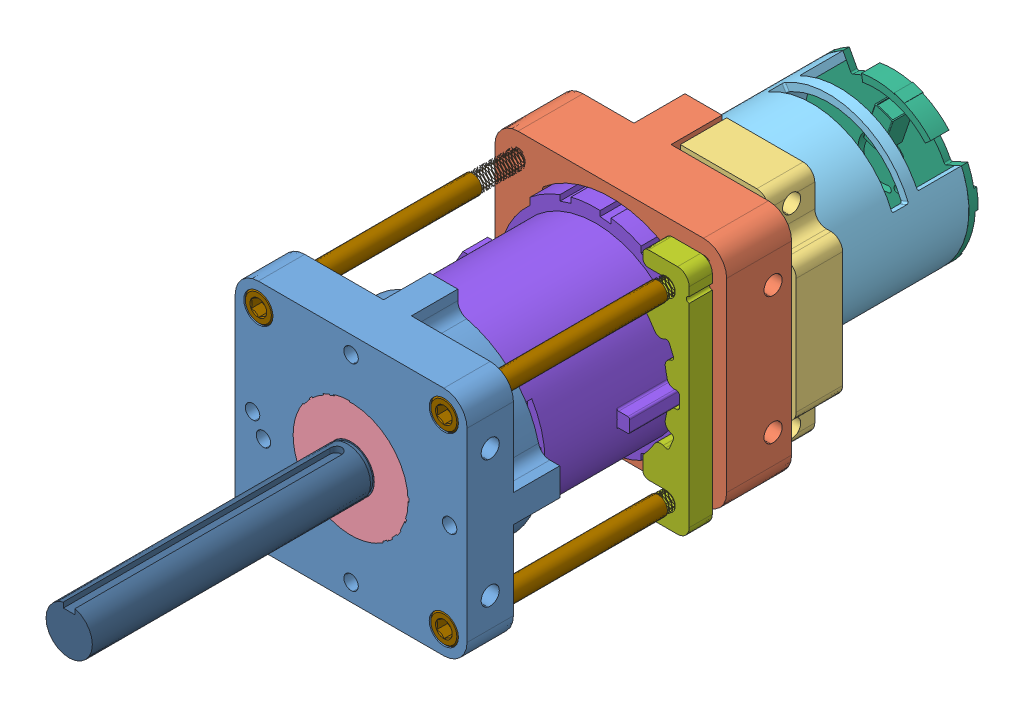
SolidWorks assembly dewut_assy, configuration Default. Lengths in mm.
Overall size (63.91 63.5 231.44).
15 component instances, 10 part files, 0 mates.
Components (placement in the parent):
- drillgb_billet_front-1: drillgb_billet_front [Default] at origin size (63.5 63.5 25.4)
- drillgb_billet_mid-1: drillgb_billet_mid [Default] at (0 0 -77.47) size (63.5 63.5 31.75)
- drillgb_billet_motor_clamp-1: drillgb_billet_motor_clamp [Default] at (0 31.75 -77.47) x (0 -1 0) z (0 0 1) size (63.5 31.75 12.7)
- fake_FR8ZZ-1: fake_FR8ZZ [Default] at (0 0 17.4625) size (31.75 31.75 7.94)
- fake_FR8ZZ-2: fake_FR8ZZ [Default] at (0 0 17.4625) x (1 0 0) z (0 0 -1) size (31.75 31.75 7.94)
- dewalt_motor-1: dewalt_motor [Default] at (0 0 -120.32) x (0.998041 0.062557 0) z (0 0 1) size (59.19 56.05 89.26)
  - dewalt_motor_shell-1: dewalt_motor_shell [Default] at origin size (47 47 80.75)
  - dewalt_motor_endcap-1: dewalt_motor_endcap [Default] x (0.92388 -0.382683 0) z (0 0 -1) size (47 41.2 14.33)
- drillgb_gear_selector_lock_layer_6_v2-1: drillgb_gear_selector_lock_layer_6_v2 [Default] at (-31.75 -31.75 -41.7842) size (12.7 63.5 6.35)
- dewalt_397892_geometry_model-1: dewalt_397892_geometry_model [Default] at (0 0 -58.039) size (57.4 56.6 65.81)
- 91251A360-1: 91251A360 [Default] at (-25.4 25.4 -55.626) x (1 0 0) z (0 0 -1) size (10.93 9.18 85.16)
- 91251A360-2: 91251A360 [Default] at (25.4 25.4 -55.626) x (1 0 0) z (0 0 -1) size (10.93 9.18 85.16)
- 91251A360-3: 91251A360 [Default] at (25.4 -25.4 -55.626) x (1 0 0) z (0 0 -1) size (10.93 9.18 85.16)
- 91251A360-4: 91251A360 [Default] at (-25.4 -25.4 -55.626) x (1 0 0) z (0 0 -1) size (10.93 9.18 85.16)
- drillgb_billet_integrated_shaft-1: drillgb_billet_integrated_shaft [Default] at (0 0 9.271) size (26.47 25.68 102.87)
